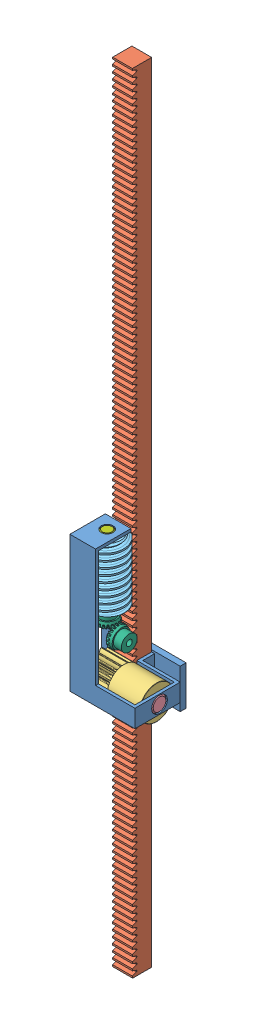
SolidWorks assembly test assem, configuration Default. Lengths in mm.
Overall size (46 400 32.12).
8 component instances, 7 part files, 14 mates.
Components (placement in the parent):
- upper rack bracket-2: upper rack bracket [Default] at origin size (46 79 32)
- 2485N201_Metal Gear Rack - 20 Degree Pressure Angle-2: 2485N201_Metal Gear Rack - 20 Degree Pressure Angle [2485N201] at (20.5 30.3933 3) x (0 -1 0) z (-1 0 0) size (400 9.8 10)
- 2664N536_Metal Gear - 20 Degree Pressure Angle-1: 2664N536_Metal Gear - 20 Degree Pressure Angle [2664N536] at (14.5 14.5 19.5) x (0 0.709382 -0.704824) z (1 0 0) size (17 17 30.01)
- 1265K64_Rotary Shaft-1: 1265K64_Rotary Shaft [33mm (upper lift bracket)] at (29.5 14.5 19.5) x (0 0 -1) z (1 0 0) size (8 8 33)
- 57545K633_Steel Worm-1: 57545K633_Steel Worm [57545K633] at (20.2199 61.5 20.303) x (0.939793 0 0.341745) z (0 -1 0) size (18.45 18.39 32.92)
- 2810N1_Plastic Miter Gear-1: 2810N1_Plastic Miter Gear [2810N1] at (20.2199 37.5 20.303) x (0 1 0) z (0.748416 0 0.66323) size (8.01 10.95 10.95)
- 2810N1_Plastic Miter Gear-2: 2810N1_Plastic Miter Gear [2810N1] at (23.5217 34.6694 20.3791) x (1 0 0) z (0 -0.624707 0.780859) size (8.01 10.95 10.95)
- Carbon steel 6 mm dia Rotary Shaft-1: Carbon steel 6 mm dia Rotary Shaft [40mm for z lift] at (20.2199 58.25 20.303) x (-0.962703 0 -0.270559) z (0 -1 0) size (6 6 41.5)
Mates (geometry in assembly coordinates):
- Concentric3: concentric aligned: circle of upper rack bracket-2; cylinder of 57545K633_Steel Worm-1 through (20.2199 77.5 20.303) axis (0 1 0) radius 3
- Concentric4: concentric anti-aligned: cylinder of upper rack bracket-2 through (20.2199 77.5 20.303) axis (0 1 0) radius 3; cylinder of 2810N1_Plastic Miter Gear-1 through (20.2199 37.5 20.303) axis (0 -1 0) radius 1.5
- Lock1: lock: unknown of 57545K633_Steel Worm-1; unknown of 2810N1_Plastic Miter Gear-1
- Coincident7: coincident anti-aligned: plane of upper rack bracket-2 through (0 77.5 0) normal (0 -1 0); plane of 57545K633_Steel Worm-1 through (20.2199 77.5 20.303) normal (0 1 0)
- Perpendicular1: perpendicular: plane of 2810N1_Plastic Miter Gear-1 through (17.9232 37.5 22.8946) normal (0 -1 0); plane of 2810N1_Plastic Miter Gear-2 through (23.5217 37.3734 22.5423) normal (-1 0 0)
- Perpendicular2: perpendicular: plane of 2810N1_Plastic Miter Gear-1 through (17.9232 37.5 22.8946) normal (0 -1 0); plane of 2810N1_Plastic Miter Gear-2 through (23.5217 37.3734 22.5423) normal (-1 0 0)
- Coincident12: coincident anti-aligned: plane of upper rack bracket-2 through (0 0 3) normal (0 0 1); plane of 2485N201_Metal Gear Rack - 20 Degree Pressure Angle-2 through (15.5 280.3933 3) normal (0 0 -1)
- Coincident13: coincident anti-aligned: plane of upper rack bracket-2 through (25.5 0 3) normal (-1 0 0); plane of 2485N201_Metal Gear Rack - 20 Degree Pressure Angle-2 through (25.5 280.3933 3) normal (1 0 0)
- Coincident15: coincident aligned: plane of upper rack bracket-2 through (46 0 0) normal (1 0 0); plane of 1265K64_Rotary Shaft-1 through (46 14.5 19.5) normal (1 0 0)
- Coincident16: coincident anti-aligned: plane of upper rack bracket-2 through (44.5 0 10.5) normal (-1 0 0); plane of 2664N536_Metal Gear - 20 Degree Pressure Angle-1 through (44.5 17.3193 22.3375) normal (1 0 0)
- Concentric7: concentric aligned: cylinder of 2664N536_Metal Gear - 20 Degree Pressure Angle-1 through (24.5 14.5 19.5) axis (-1 0 0) radius 8.5; cylinder of 1265K64_Rotary Shaft-1 through (46 14.5 19.5) axis (-1 0 0) radius 4
- Coincident18: coincident aligned: cylinder of upper rack bracket-2 through (46 14.5 19.5) axis (-1 0 0) radius 4; circle of 1265K64_Rotary Shaft-1
- Concentric8: concentric aligned: cylinder of 57545K633_Steel Worm-1 through (20.2199 77.5 20.303) axis (0 1 0) radius 3; cylinder of Carbon steel 6 mm dia Rotary Shaft-1 through (20.2199 37.5 20.303) axis (0 1 0) radius 3
- Coincident19: coincident aligned: plane of upper rack bracket-2 through (0 79 0) normal (0 1 0); plane of Carbon steel 6 mm dia Rotary Shaft-1 through (20.2199 79 20.303) normal (0 1 0)
